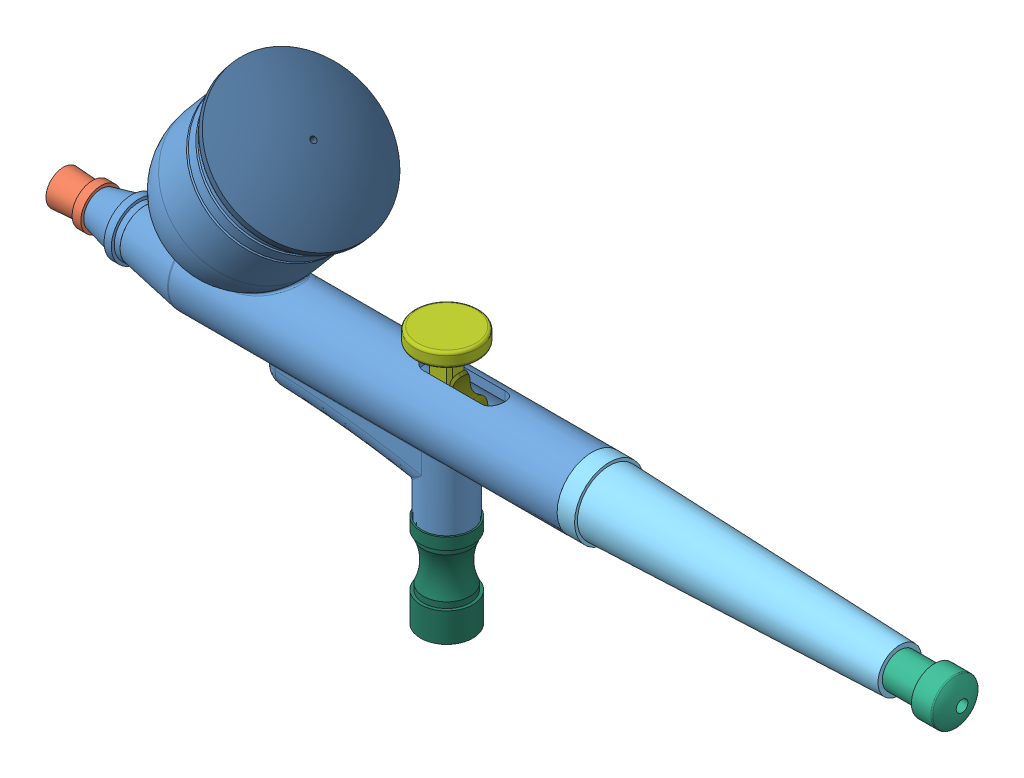
SolidWorks assembly Aerografo, configuration Valor predeterminado. Lengths in mm.
Overall size (154.73 72.05 35.62).
28 component instances, 28 part files, 63 mates.
Components (placement in the parent):
- Corpo 1-1: Corpo 1 [Valor predeterminado] at (-54.0783 -2.0658 80) size (80 49.19 25)
- Encaixe_Agulha-1: Encaixe_Agulha [Valor predeterminado] at (14.9217 -2.0658 80) x (-1 0 0) z (0 0 1) size (4 9 9)
- Parafuso-1: Parafuso [Valor predeterminado] at (13.8087 -3.2658 80.4618) x (-0.887002 0 -0.461767) z (-0.461767 0 0.887002) size (4 5.16 4)
- Fixação_Agulha_3-1: Fixação_Agulha_3 [Valor predeterminado] at (5.3054 -2.0658 80) x (1 0 0) z (0 -1 0) size (42.04 5 5)
- Mola_Agulha-1: Mola_Agulha [Valor predeterminado] at (17.3054 -2.0658 80) x (0 -0.999777 -0.021106) z (0 -0.021106 0.999777) size (5.15 14.82 5.77)
- Fixação_Agulha_2-1: Fixação_Agulha_2 [Valor predeterminado] at (14.9217 -2.0658 80) x (1 0 0) z (0 -0.937211 0.348763) size (18 9 9)
- Alavanca-1: Alavanca [Valor predeterminado] at (-1.0783 6.1935 80) x (0 -1 0) z (0 0 1) size (17 11 11)
- Alavanca_Mecanismo-1: Alavanca_Mecanismo [Valor predeterminado] at (0.9217 -13.3065 80) x (0 0 -1) z (1 0 0) size (2 8.5 3)
- Rebite-1: Rebite [Valor predeterminado] at (0.9217 -5.8065 80) size (1 1 3)
- Eixo_Valvula-1: Eixo_Valvula [Valor predeterminado] at (0.9217 -31.3065 80) x (-0.831662 0 -0.555282) z (0.555282 0 -0.831662) size (4.5 18.5 4.5)
- Mola_Valvula-1: Mola_Valvula [Valor predeterminado] at (0.9217 -16.8065 80) x (-0.392534 0 -0.919737) z (-0.919737 0 0.392534) size (3.81 13.46 4.27)
- O-ring_Válvula 1-1: O-ring_Válvula 1 [Valor predeterminado] at (0.9217 -16.3065 80) x (-0.831662 0 -0.555282) z (0 1 0) size (4.5 4.5 1)
- O-ring_Válvula 2-1: O-ring_Válvula 2 [Valor predeterminado] at (0.9217 -18.0658 80) x (0.996046 0 0.088843) z (0 1 0) size (7 7 1)
- Tampa_Válvula-1: Tampa_Válvula [Valor predeterminado] at (0.9217 -30.0658 80) x (-0.831662 0 -0.555282) z (0 1 0) size (4.39 4.5 0.5)
- Valvula-1: Valvula [Valor predeterminado] at (0.9217 -14.0658 80) x (0.996046 0 0.088843) z (-0.088843 0 0.996046) size (9 20 9)
- Placa_Mola-2: Placa_Mola [Valor predeterminado] at (3.6284 -5.6712 76.75) x (0 0 1) z (-0.97249 -0.232944 0) size (6.17 10.12 2.5)
- O-ring_Bico-1: O-ring_Bico [Valor predeterminado] at (-51.3283 -2.0658 80) x (0 0 -1) z (1 0 0) size (7.5 7.5 0.25)
- O-ring_Corpo-1: O-ring_Corpo [Valor predeterminado] at (0.9217 -12.0658 80) x (0.999142 0 0.041416) z (0 -1 0) size (4 4 0.5)
- Bico 1-1: Bico 1 [Valor predeterminado] at (-61.0783 -2.0658 80) size (10 9.5 9.5)
- Bico 2-1: Bico 2 [Valor predeterminado] at (-65.0783 -2.0658 80) x (1 0 0) z (0 0.382891 0.923793) size (6.5 7 7)
- Biqueira-1: Biqueira [Valor predeterminado] at (-61.0783 -2.0658 80) x (1 0 0) z (0 0.183184 0.983079) size (6.2 3 3)
- Biqueira 2-1: Biqueira 2 [Valor predeterminado] at (-56.0783 -2.0658 80) x (1 0 0) z (0 0.973222 0.229866) size (10 5 5)
- Corpo 2-1: Corpo 2 [Valor predeterminado] at (21.9217 -2.0658 80) x (1 0 0) z (0 0.71215 0.702027) size (57 12 12)
- Encaixe_Fundo-1: Encaixe_Fundo [Valor predeterminado] at (57.7217 -2.0658 80) size (31.93 8 8)
- Fixação_Agulha-1: Fixação_Agulha [Valor predeterminado] at (51.1502 -2.0658 80) x (-1 0 0) z (0 -0.904496 -0.426482) size (10 6 6)
- O-Ring_Encaixe_Fundo-1: O-Ring_Encaixe_Fundo [Valor predeterminado] at (77.7217 -2.0658 80) x (0 0 -1) z (1 0 0) size (6 6 1.2)
- Agulha-1: Agulha [Valor predeterminado] at (-61.3498 -2.0658 80) x (1 0 0) z (0 0.994994 0.099935) size (128.5 1 1)
- Tampa-1: Tampa [Valor predeterminado] at (-27.1715 20.4042 80) x (-0.310383 0.260442 0.914239) z (-0.700348 0.587661 -0.405176) size (27 8 27)
Mates (geometry in assembly coordinates):
- Concêntrico1: concentric aligned: circle of Corpo 1-1; circle of Encaixe_Agulha-1
- Concêntrico2: concentric anti-aligned: cylinder of Corpo 1-1 through (12.9217 -8.0658 80) axis (0 1 0) radius 2; cylinder of Encaixe_Agulha-1 through (12.9217 -6.5658 80) axis (0 -1 0) radius 1
- Concêntrico3: concentric aligned: cylinder of Encaixe_Agulha-1 through (12.9217 -6.5658 80) axis (0 -1 0) radius 1; cylinder of Parafuso-1 through (12.9217 -8.2658 80) axis (0 -1 0) radius 1
- Concêntrico4: concentric anti-aligned: circle of Corpo 1-1; circle of Fixação_Agulha_3-1
- Coincidente3: coincident anti-aligned: plane of Parafuso-1 through (12.9217 -3.2658 80) normal (0 1 0); plane of Fixação_Agulha_3-1 through (15.6054 -3.2658 80) normal (0 -1 0)
- DistânciaLimite1: limit distance = 0.1837 mm: cylinder of Parafuso-1 through (12.9217 -8.2658 80) axis (0 -1 0) radius 1; cylinder of Fixação_Agulha_3-1 through (15.6054 -13.2658 80) axis (0 1 0) radius 1.5
- DistânciaLimite2: limit distance = 31.8837 mm: plane of Fixação_Agulha_3-1 through (45.8054 -2.0658 81.75) normal (1 0 0); cylinder of Parafuso-1 through (12.9217 -8.2658 80) axis (0 -1 0) radius 1
- Concêntrico6: concentric aligned: cylinder of Fixação_Agulha_3-1 through (47.3054 -2.0658 80) axis (1 0 0) radius 1.75; line of Mola_Agulha-1 through (17.3054 -2.0658 80) axis (1 0 0)
- Coincidente5: coincident anti-aligned: plane of Fixação_Agulha_3-1 through (17.3054 -2.0658 82.5) normal (1 0 0); plane of Mola_Agulha-1 through (17.3054 -2.0658 80) normal (-1 0 0)
- Concêntrico7: concentric anti-aligned: circle of Corpo 1-1; circle of Fixação_Agulha_2-1
- Coincidente6: coincident anti-aligned: plane of Encaixe_Agulha-1 through (14.9217 -6.5658 80) normal (1 0 0); plane of Fixação_Agulha_2-1 through (14.9217 -2.0658 80) normal (-1 0 0)
- Concêntrico8: concentric anti-aligned: circle of Alavanca-1; circle of Alavanca_Mecanismo-1
- Coincidente8: coincident anti-aligned: plane of Alavanca-1 through (-1.0783 -6.8065 80.75) normal (0 0 -1); plane of Alavanca_Mecanismo-1 through (0.9217 -13.3065 80.75) normal (0 0 1)
- Concêntrico9: concentric aligned: circle of Alavanca-1; circle of Rebite-1
- Coincidente10: coincident aligned: circle of Alavanca-1; circle of Rebite-1
- Concêntrico11: concentric anti-aligned: circle of Corpo 1-1; circle of Alavanca_Mecanismo-1
- ÂnguloLimite2: limit planar angle = 0 rad aligned: line of Alavanca-1 through (-0.5783 6.1935 78.5) axis (0 -1 0); cylinder of Alavanca_Mecanismo-1 through (0.9217 -13.3065 80) axis (0 -1 0) radius 1
- Paralelo6: parallel anti-aligned: plane of Corpo 1-1 through (10.9217 31.1202 78) normal (0 0 1); plane of Alavanca-1 through (0.9217 -4.8065 78.5) normal (0 0 -1)
- DistânciaLimite3: limit distance = 0.2407 mm: cylinder of Alavanca_Mecanismo-1 through (-0.0783 -6.3065 79.25) axis (0 0 1) radius 0.5; cylinder of Corpo 1-1 through (9.9217 -2.0658 80) axis (1 0 0) radius 4.5
- DistânciaLimite5: limit distance = 4.7593 mm aligned: plane of Alavanca_Mecanismo-1 through (0.9217 -13.3065 80) normal (0 -1 0); plane of Corpo 1-1 through (0.9217 -18.0658 80) normal (0 -1 0)
- Concêntrico13: concentric aligned: cylinder of Eixo_Valvula-1 through (0.9217 -31.3065 80) axis (0 -1 0) radius 1.5; line of Mola_Valvula-1 through (0.9217 -16.8065 80) axis (0 -1 0)
- Coincidente15: coincident anti-aligned: plane of Eixo_Valvula-1 through (-0.9495 -16.8065 78.7506) normal (0 -1 0); plane of Mola_Valvula-1 through (0.9217 -16.8065 80) normal (0 1 0)
- Concêntrico14: concentric anti-aligned: circle of Eixo_Valvula-1; circle of Tampa_Válvula-1
- Concêntrico15: concentric anti-aligned: circle of O-ring_Válvula 2-1; circle of Valvula-1
- Coincidente18: coincident anti-aligned: plane of O-ring_Válvula 2-1 through (0.9217 -18.0658 80) normal (0 -1 0); plane of Valvula-1 through (-1.7676 -18.0658 79.7601) normal (0 1 0)
- Concêntrico16: concentric anti-aligned: circle of Eixo_Valvula-1; circle of O-ring_Válvula 1-1
- Coincidente20: coincident anti-aligned: plane of Eixo_Valvula-1 through (0.298 -16.3065 79.5835) normal (0 1 0); plane of O-ring_Válvula 1-1 through (0.9217 -16.3065 80) normal (0 -1 0)
- Concêntrico17: concentric aligned: circle of Eixo_Valvula-1; circle of Valvula-1
- DistânciaLimite6: limit distance = 21.2593 mm anti-aligned: plane of Eixo_Valvula-1 through (0.9217 -12.8065 80) normal (0 1 0); plane of Valvula-1 through (-3.5605 -34.0658 79.6002) normal (0 -1 0)
- Coincidente22: coincident anti-aligned: circle of Tampa_Válvula-1; circle of Valvula-1
- Concêntrico18: concentric aligned: circle of Alavanca_Mecanismo-1; circle of Eixo_Valvula-1
- Coincidente24: coincident anti-aligned: plane of Alavanca_Mecanismo-1 through (0.9217 -12.8065 80) normal (0 -1 0); plane of Eixo_Valvula-1 through (0.9217 -12.8065 80) normal (0 1 0)
- Coincidente25: coincident anti-aligned: plane of Corpo 1-1 through (0.9217 -18.0658 80) normal (0 -1 0); plane of Valvula-1 through (-1.7676 -18.0658 79.7601) normal (0 1 0)
- Paralelo7: parallel aligned: plane of Corpo 1-1 through (10.9217 31.1202 78) normal (0 0 1); plane of Placa_Mola-2 through (9.2507 -1.2396 79) normal (0 0 1)
- Coincidente27: coincident: point of Alavanca-1; unknown of Placa_Mola-2
- Tangente9: tangent anti-aligned: plane of Alavanca-1 through (2.9217 6.1935 81.5) normal (1 0 0); cylinder of Placa_Mola-2 through (7.2368 2.7923 83.25) axis (0 0 -1) radius 4.3151
- Tangente17: tangent anti-aligned: plane of Fixação_Agulha_3-1 through (5.3054 -2.0658 80) normal (-1 0 0); cylinder of Placa_Mola-2 through (0.3288 -2.6458 83.25) axis (0 0 -1) radius 4.9766
- Distância6: distance = 8.3945 mm: line of Placa_Mola-2 through (3.6284 -5.6712 81.55) axis (0 0 -1); plane of Valvula-1 through (0.9217 -14.0658 80) normal (0 1 0)
- DistânciaLimite9: limit distance = 0.8414 mm: line of Placa_Mola-2 through (3.6284 -5.6712 81.55) axis (0 0 -1); cylinder of Alavanca-1 through (0.9217 -4.8065 81.5) axis (0 0 -1) radius 2
- Concêntrico26: concentric anti-aligned: circle of Corpo 1-1; circle of O-ring_Corpo-1
- Coincidente43: coincident anti-aligned: plane of Corpo 1-1 through (0.9217 -12.0658 80) normal (0 -1 0); plane of O-ring_Corpo-1 through (0.9217 -12.0658 80) normal (0 1 0)
- Concêntrico28: concentric anti-aligned: circle of Corpo 1-1; circle of O-ring_Bico-1
- Coincidente46: coincident anti-aligned: plane of Corpo 1-1 through (-51.0783 1.6842 80) normal (-1 0 0); plane of O-ring_Bico-1 through (-51.0783 -2.0658 80) normal (1 0 0)
- Concêntrico29: concentric aligned: circle of Corpo 1-1; circle of Biqueira 2-1
- Coincidente48: coincident anti-aligned: plane of Corpo 1-1 through (-46.0783 -5.5658 80) normal (-1 0 0); plane of Biqueira 2-1 through (-46.0783 -1.4911 77.5669) normal (1 0 0)
- Concêntrico30: concentric anti-aligned: circle of Biqueira-1; circle of Biqueira 2-1
- Coincidente50: coincident anti-aligned: plane of Biqueira-1 through (-56.0783 -0.5912 79.7252) normal (1 0 0); plane of Biqueira 2-1 through (-56.0783 -2.0658 80) normal (-1 0 0)
- Concêntrico31: concentric aligned: circle of Fixação_Agulha_2-1; circle of Agulha-1
- Concêntrico32: concentric anti-aligned: circle of Corpo 1-1; circle of Fixação_Agulha-1
- Distância9: distance = 16 mm aligned: plane of Agulha-1 through (67.1502 -2.0158 79.5025) normal (1 0 0); plane of Fixação_Agulha-1 through (51.1502 -2.0658 80) normal (1 0 0)
- Bloquear1: lock: unknown of Fixação_Agulha_3-1; unknown of Fixação_Agulha-1
- Concêntrico34: concentric aligned: circle of Corpo 1-1; circle of Bico 1-1
- Coincidente55: coincident anti-aligned: plane of Corpo 1-1 through (-51.0783 1.6842 80) normal (-1 0 0); plane of Bico 1-1 through (-51.0783 2.1842 80) normal (1 0 0)
- Concêntrico35: concentric anti-aligned: circle of Bico 1-1; circle of Bico 2-1
- Coincidente56: coincident anti-aligned: plane of Bico 1-1 through (-58.5783 -0.0658 80) normal (-1 0 0); plane of Bico 2-1 through (-58.5783 1.1675 78.6599) normal (1 0 0)
- Concêntrico36: concentric aligned: circle of Corpo 1-1; circle of Corpo 2-1
- Coincidente57: coincident anti-aligned: plane of Corpo 1-1 through (25.9217 3.9342 80) normal (1 0 0); plane of Corpo 2-1 through (25.9217 1.0934 76.7953) normal (-1 0 0)
- Concêntrico37: concentric anti-aligned: circle of Encaixe_Fundo-1; circle of O-Ring_Encaixe_Fundo-1
- Coincidente58: coincident anti-aligned: circle of Encaixe_Fundo-1; circle of O-Ring_Encaixe_Fundo-1
- Concêntrico38: concentric anti-aligned: circle of Corpo 2-1; circle of Encaixe_Fundo-1
- Coincidente59: coincident aligned: circle of Corpo 2-1; circle of Encaixe_Fundo-1
- Concêntrico39: concentric anti-aligned: circle of Corpo 1-1; circle of Tampa-1
- DistânciaLimite10: limit distance = 0 mm anti-aligned: plane of Tampa-1 through (-21.3524 20.0903 69.4863) normal (-0.642788 -0.766044 0); plane of Corpo 1-1 through (-24.9218 23.0853 80) normal (0.642788 0.766044 0)
